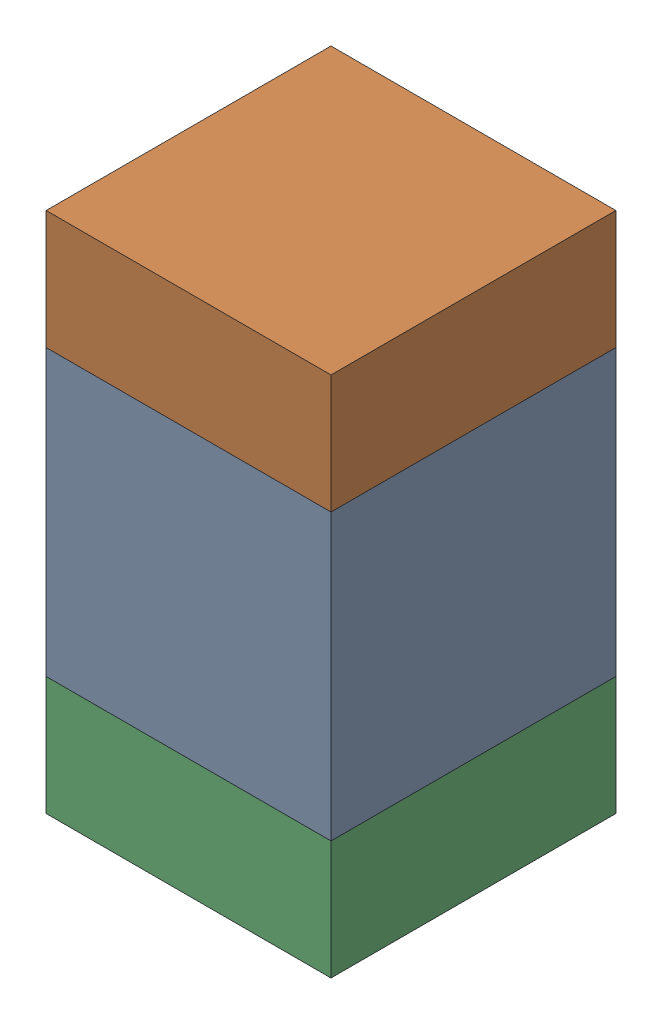
SolidWorks assembly C118_1PCB, configuration Default. Lengths in mm.
Overall size (0.6 1.1 0.6).
6 component instances, 2 part files, 0 mates.
Components (placement in the parent):
- 761606048-1: 761606048 [Default] at (114.8 115.5 0) size (0.6 0.6 0.6)
  - Extruded_9-1: Extruded_9 [Default] at origin size (0.6 0.6 0.6)
- 854785296-1: 854785296 [Default] at (114.8 115.925 0) size (0.6 0.25 0.6)
  - Extruded_10-1: Extruded_10 [Default] at origin size (0.6 0.25 0.6)
- 854785296-2: 854785296 [Default] at (114.8 115.075 0) size (0.6 0.25 0.6)
  - Extruded_10-1: Extruded_10 [Default] at origin size (0.6 0.25 0.6)
